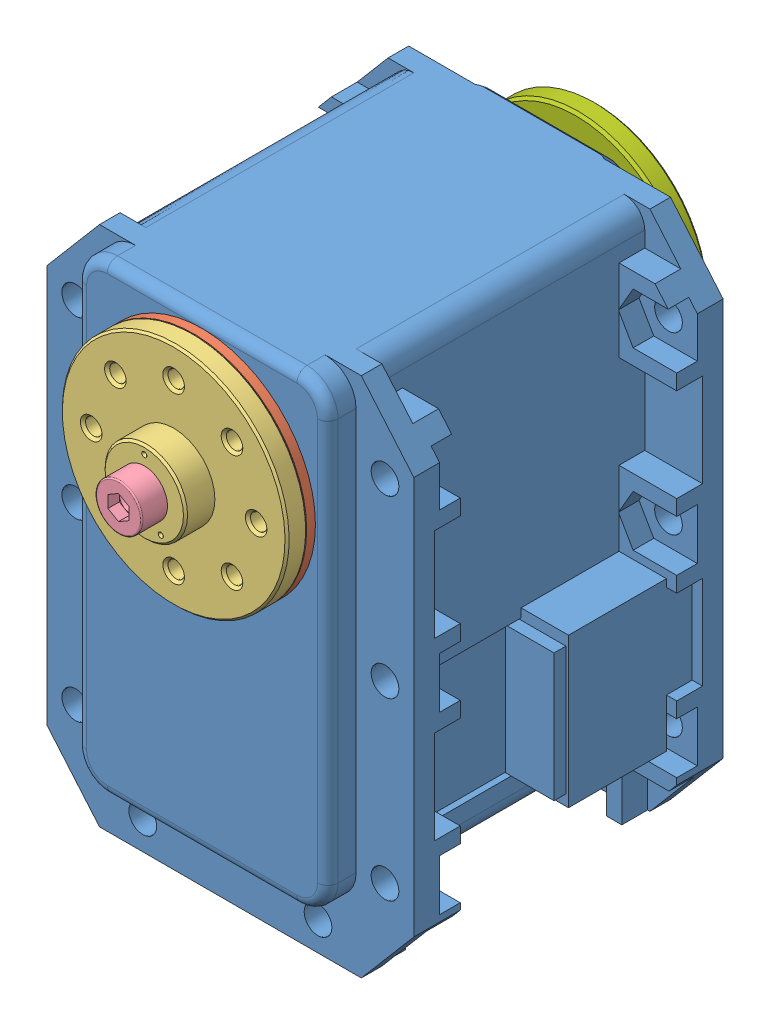
SolidWorks assembly MX-28, configuration U. Lengths in mm.
Overall size (35.6 51.1 48.5).
8 component instances, 7 part files, 15 mates.
Components (placement in the parent):
- dynamixel_x28series-1: dynamixel_x28series [U] at (-36.1865 18.4113 -1.675) size (35.6 50.71 41.85)
- trust_washer-1: trust_washer [U] at (-36.1865 18.4113 16.925) x (0.989151 -0.146904 0) z (0.146904 0.989151 0) size (22 0.85 22)
- HN07-N101-1: HN07-N101 [U] at (-36.1865 18.4113 16.825) x (1 0 0) z (0 -1 0) size (22 5.85 22)
- WB_M2.5x8-1: WB_M2.5x8 [ISO 4762 M2.5 x 8 --- 8N] at (-36.1865 18.4113 24.175) x (0 0 -1) z (1 0 0)
- RX28-CAP-1: RX28-CAP [Défaut] at (-36.1865 18.4113 -22.025) x (-0.979131 -0.20323 0) z (0 0 -1)
- MF106ZZ-1: MF106ZZ [Défaut] at (-36.1865 18.4113 -22.025) x (1 0 0) z (0 -1 0)
- WB_M2.5x8-3: WB_M2.5x8 [ISO 4762 M2.5 x 8 --- 8N] at (-36.1865 18.4113 -24.325) x (0 0 1) z (-1 0 0)
- HN07-i101-1: HN07-i101 [Défaut] at (-36.1865 18.4113 -22.175) x (1 0 0) z (0 1 0)
Mates (geometry in assembly coordinates):
- Concentric1: concentric anti-aligned: cylinder of dynamixel_x28series-1 through (-36.1865 18.4113 16.075) axis (0 0 1) radius 2.85; cylinder of trust_washer-1 through (-36.1865 18.4113 16.925) axis (0 0 -1) radius 4
- Concentric2: concentric anti-aligned: cylinder of dynamixel_x28series-1 through (-36.1865 18.4113 16.075) axis (0 0 1) radius 2.85; cylinder of HN07-N101-1 through (-36.1865 18.4113 21.9675) axis (0 0 -1) radius 4
- Coincident1: coincident anti-aligned: plane of dynamixel_x28series-1 through (-36.1865 18.4113 16.075) normal (0 0 1); plane of trust_washer-1 through (-32.2299 17.8237 16.075) normal (0 0 -1)
- Angle1: planar angle = 0 rad aligned: plane of dynamixel_x28series-1 through (-36.1865 18.4113 -1.675) normal (1 0 0); plane of HN07-N101-1
- Concentric3: concentric anti-aligned: line of dynamixel_x28series-1 through (-36.1865 18.4113 -28.9561) axis (0 0 1); cylinder of RX28-CAP-1 through (-36.1865 18.4113 -21.025) axis (0 0 -1) radius 1.35
- Concentric9: concentric aligned: line of dynamixel_x28series-1 through (-36.1865 18.4113 -28.9561) axis (0 0 1); cylinder of MF106ZZ-1 through (-36.1865 18.4113 -22.025) axis (0 0 1) radius 3
- Coincident7: coincident anti-aligned: plane of RX28-CAP-1 through (-39.6135 17.7 -22.025) normal (0 0 1); plane of MF106ZZ-1 through (-30.5865 18.4113 -22.025) normal (0 0 -1)
- Concentric111: concentric aligned: cone of HN07-N101-1 through (-36.1865 18.4113 21.475) axis (0 0 1); cylinder of WB_M2.5x8-1 through (-36.1865 18.4113 55.925) axis (0 0 1) radius 2.25
- Coincident91: coincident anti-aligned: plane of HN07-N101-1 through (-36.1865 18.4113 21.675) normal (0 0 1); plane of WB_M2.5x8-1 through (-36.1865 20.6613 21.675) normal (0 0 -1)
- Concentric121: concentric anti-aligned: cone of RX28-CAP-1 through (-36.1865 18.4113 -21.725) axis (0 0 1); cylinder of WB_M2.5x8-3 through (-36.1865 18.4113 -56.075) axis (0 0 -1) radius 2.25
- Coincident101: coincident anti-aligned: plane of RX28-CAP-1 through (-37.6063 18.1166 -21.825) normal (0 0 -1); plane of WB_M2.5x8-3 through (-36.1865 20.6613 -21.825) normal (0 0 1)
- Concentric13: concentric anti-aligned: cylinder of MF106ZZ-1 through (-36.1865 18.4113 -22.025) axis (0 0 1) radius 5; cylinder of HN07-i101-1 through (-36.1865 18.4113 -22.175) axis (0 0 -1) radius 5
- Distance1: distance = 41 mm anti-aligned: plane of HN07-i101-1 through (-25.1865 18.4113 -22.175) normal (0 0 -1); plane of HN07-N101-1 through (-36.1865 18.4113 18.825) normal (0 0 1)
- Distance2: distance = 2.75 mm aligned: plane of HN07-N101-1 through (-36.1865 18.4113 18.825) normal (0 0 1); plane of dynamixel_x28series-1 through (-36.1865 18.4113 16.075) normal (0 0 1)
- Concentric122: concentric anti-aligned: cylinder of HN07-N101-1 through (-36.1865 26.4113 18.825) axis (0 0 1) radius 0.8; cylinder of HN07-i101-1 through (-36.1865 26.4113 -22.175) axis (0 0 -1) radius 0.8
